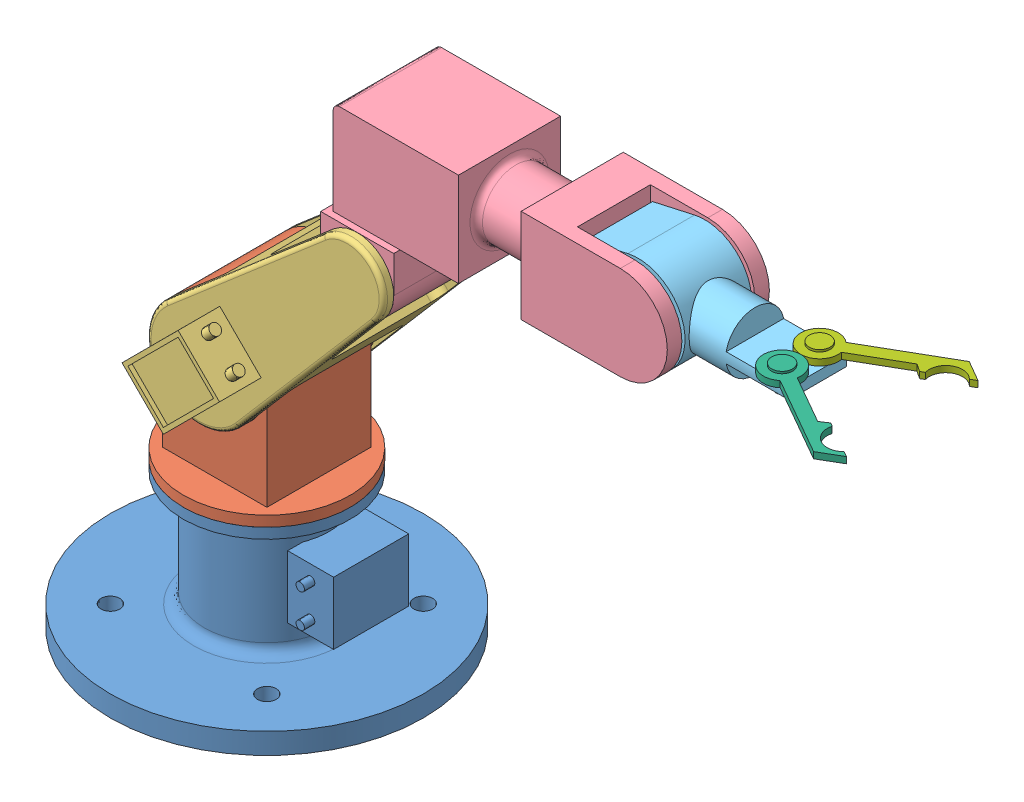
SolidWorks assembly Robot Kol Montaj, configuration Varsayılan. Lengths in mm.
Overall size (385.09 258.21 150).
7 component instances, 7 part files, 13 mates.
Components (placement in the parent):
- Robot Kol 001-1: Robot Kol 001 [Varsayılan] at (-46.6543 -35.372 100) size (150 70 150)
- Robot Kol 002-1: Robot Kol 002 [Varsayılan] at (-46.6543 -20.372 100) x (0.999999 0 -0.001155) z (0.001155 0 0.999999) size (80 135 80)
- Robot Kol 003-2: Robot Kol 003 [Varsayılan] at (-46.6543 89.628 100) x (0.707106 0.707107 -0.000817) z (0.001155 0 0.999999) size (142.5 50 85)
- Robot Kol 004-1: Robot Kol 004 [Varsayılan] at (24.0564 160.3387 99.9183) x (0.999999 0 -0.001155) z (0.001155 0 0.999999) size (163 80 55)
- Robot Kol 005-2: Robot Kol 005 [Varsayılan] at (147.0563 200.3387 99.7762) x (0.999999 0 -0.001155) z (0.001155 0 0.999999) size (95 45 32)
- Robot Kol 006-1: Robot Kol 006 [Varsayılan] at (209.0666 202.8387 108.7046) x (0.867843 0 0.496838) z (-0.496838 0 0.867843) size (66.49 11 18)
- AynalamaRobot Kol 006-2: AynalamaRobot Kol 006 [Varsayılan] at (209.0458 202.8387 90.7046) x (0.866693 0 -0.498842) z (0.498842 0 0.866693) size (66.49 11 18)
Mates (geometry in assembly coordinates):
- Eş Merkezli2: concentric aligned: cylinder of Robot Kol 001-1 through (-46.6543 34.628 100) axis (0 -1 0) radius 22.5; cylinder of Robot Kol 002-1 through (-46.6543 39.628 100) axis (0 -1 0) radius 22.5
- Çakışık2: coincident anti-aligned: plane of Robot Kol 001-1 through (-46.6543 34.628 100) normal (0 1 0); plane of Robot Kol 002-1 through (-46.6543 34.628 100) normal (0 -1 0)
- Eş Merkezli3: concentric anti-aligned: cylinder of Robot Kol 002-1 through (-61.2457 89.628 62.7563) axis (0.364784 0 0.931092) radius 8; cylinder of Robot Kol 003-2 through (-34.7988 89.628 130.2605) axis (-0.364784 0 -0.931092) radius 8
- Genişlik1: width aligned: plane of Robot Kol 003-2 through (-18.0059 95.8152 59.2409) normal (0.364784 0 0.931092); plane of Robot Kol 002-1 through (2.0572 95.8152 110.451) normal (-0.364784 0 -0.931092); plane of Robot Kol 003-2 through (-36.6227 89.628 125.605) normal (0.364784 0 0.931092); plane of Robot Kol 002-1 through (-56.6858 89.628 74.395) normal (-0.364784 0 -0.931092)
- Eş Merkezli4: concentric aligned: cylinder of Robot Kol 003-2 through (31.0394 160.3387 104.4663) axis (-0.364784 0 -0.931092) radius 8; cylinder of Robot Kol 004-1 through (29.2154 160.3387 99.8109) axis (-0.364784 0 -0.931092) radius 8
- Genişlik2: width anti-aligned: plane of Robot Kol 003-2 through (-58.5098 89.628 69.7395) normal (-0.364784 0 -0.931092); plane of Robot Kol 004-1 through (-34.7988 89.628 130.2605) normal (0.364784 0 0.931092); plane of Robot Kol 003-2 through (70.4858 222.8387 80.4199) normal (0.364784 0 0.931092); plane of Robot Kol 004-1 through (52.6113 222.8387 34.7964) normal (-0.364784 0 -0.931092)
- Eş Merkezli5: concentric aligned: cylinder of Robot Kol 004-1 through (140.0919 200.3387 45.6315) axis (-0.364784 0 -0.931092) radius 6; cylinder of Robot Kol 005-2 through (139.5447 200.3387 44.2349) axis (-0.364784 0 -0.931092) radius 6
- Genişlik3: width anti-aligned: plane of Robot Kol 004-1 through (80.5441 177.8387 23.8529) normal (-0.364784 0 -0.931092); plane of Robot Kol 005-2 through (163.595 177.8387 43.9415) normal (0.364784 0 0.931092); plane of Robot Kol 004-1 through (139.5447 200.3387 44.2349) normal (0.364784 0 0.931092); plane of Robot Kol 005-2 through (127.8716 200.3387 14.4399) normal (-0.364784 0 -0.931092)
- Eş Merkezli6: concentric aligned: cylinder of Robot Kol 005-2 through (194.719 172.8387 15.1006) axis (0 1 0) radius 3; cylinder of Robot Kol 006-1 through (194.719 205.8387 15.1006) axis (0 1 0) radius 3
- Çakışık3: coincident anti-aligned: plane of Robot Kol 005-2 through (198.8846 202.8387 3.8025) normal (0 1 0); plane of Robot Kol 006-1 through (194.719 202.8387 15.1006) normal (0 -1 0)
- Açıyı Sınırla1: limit planar angle = 0.785398 rad aligned: plane of Robot Kol 003-2 through (-46.6543 89.628 100) normal (-0.707106 0.707107 0.000817); plane of Robot Kol 001-1 through (-46.6543 -25.372 100) normal (0 1 0)
- Açıyı Sınırla2: limit planar angle = 2.620486 rad anti-aligned: plane of Robot Kol 006-1 through (252.4596 202.8387 137.0039) normal (-0.496838 0 0.867843); plane of Robot Kol 005-2 through (147.0748 200.3387 115.7762) normal (0.001155 0 0.999999)
- Açıyı Sınırla3: limit planar angle = 0 rad aligned: plane of Robot Kol 005-2 through (217.0562 202.8387 99.6954) normal (0 1 0); plane of Robot Kol 004-1 through (24.0564 222.8387 99.9183) normal (0 1 0)
